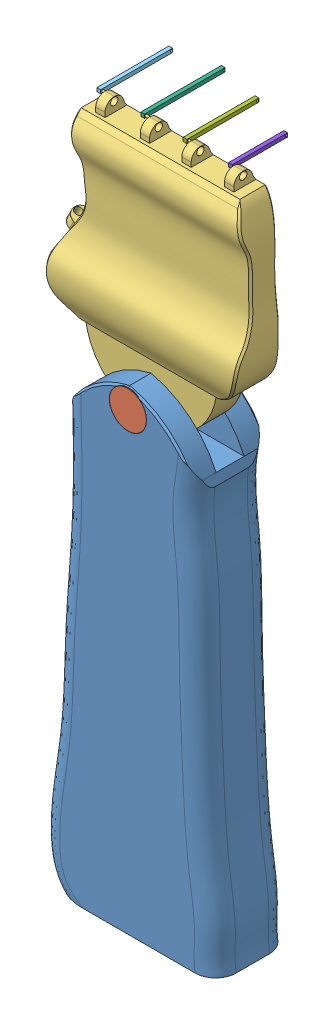
SolidWorks assembly Assem1, configuration Default. Lengths in mm.
Overall size (1345.11 2370.32 3373.58).
8 component instances, 8 part files, 14 mates.
Components (placement in the parent):
- arm2-1: arm2 [Default] at (-234.1441 930.3208 2564.8696) x (1 0 0) z (0 -1 0) size (1268.57 632.71 2564.87)
- armpin2-1: armpin2 [Default] at (-234.1441 1110.3208 2364.8696) size (200 200 400)
- palm2-1: palm2 [Default] at (-193.4419 1800.3208 2458.7662) x (1 0 0) z (0 -1 0) size (1069.09 253.19 1333.97)
- llink2palmThumb-1: llink2palmThumb [Default] at (-757.3795 1540.6952 2271.7924) x (0.892018 -0.452 0) z (0 0 1) size (20 20 462)
- link1palm-1: link1palm [Default] at (-638.703 2260.3208 2313.2524) x (0 1 0) z (0 0 1) size (20 20 387)
- llinkMiddle-1: llinkMiddle [Default] at (-406.703 2260.3208 2286.0724) x (0 1 0) z (0 0 1) size (20 20 434)
- llink2palmRing-1: llink2palmRing [Default] at (-175.0526 2260.3208 2313.2524) x (0 1 0) z (0 0 1) size (20 20 387)
- linklittle-1: linklittle [Default] at (64.9474 2260.3208 2353.4824) x (0 1 0) z (0 0 1) size (20 20 298)
Mates (geometry in assembly coordinates):
- Concentric1: concentric: cylinder of assembly; cylinder of assembly; cylinder of arm2-1 through (-234.1441 1110.3208 2364.8696) axis (0 0 1) radius 100; cylinder of armpin2-1 through (-234.1441 1110.3208 2764.8696) axis (0 0 -1) radius 100
- Coincident1: coincident: plane of assembly; plane of assembly; plane of arm2-1 through (-234.1441 930.3208 2764.8696) normal (0 0 1); plane of armpin2-1 through (-234.1441 1110.3208 2764.8696) normal (0 0 1)
- Concentric2: concentric: cylinder of assembly; cylinder of assembly; cylinder of armpin2-1 through (-234.1441 1110.3208 2764.8696) axis (0 0 -1) radius 100; cylinder of palm2-1 through (-234.1441 1110.3208 2450.7496) axis (0 0 1) radius 100
- Coincident2: coincident: plane of assembly; plane of assembly; plane of arm2-1 through (-584.1441 930.3208 2640.3696) normal (0 0 -1); plane of palm2-1 through (-584.1441 980.3208 2640.3696) normal (0 0 1)
- Concentric5: concentric: cylinder of assembly; cylinder of assembly; cylinder of palm2-1 through (-757.3795 1540.6952 2495.7524) axis (0.452 0.892018 0) radius 5.75; cylinder of llink2palmThumb-1 through (-757.3795 1540.6952 2495.7524) axis (0.452 0.892018 0) radius 5.75
- Concentric6: concentric: cylinder of assembly; cylinder of assembly; cylinder of palm2-1 through (-658.703 2260.3208 2495.7524) axis (1 0 0) radius 5.75; cylinder of link1palm-1 through (-638.703 2260.3208 2495.7524) axis (-1 0 0) radius 5.75
- Coincident5: coincident: plane of assembly; plane of assembly; plane of palm2-1 through (-658.703 2260.3208 2495.7524) normal (-1 0 0); plane of link1palm-1 through (-658.703 2260.3208 2313.2524) normal (-1 0 0)
- Coincident6: coincident: plane of assembly; plane of assembly; plane of palm2-1 through (-757.3795 1540.6952 2495.7524) normal (-0.452 -0.892018 0); plane of llink2palmThumb-1 through (-757.3795 1540.6952 2271.7924) normal (-0.452 -0.892018 0)
- Concentric7: concentric: cylinder of assembly; cylinder of assembly; cylinder of palm2-1 through (-426.703 2260.3208 2495.7524) axis (1 0 0) radius 5.75; cylinder of llinkMiddle-1 through (-406.703 2260.3208 2495.7524) axis (-1 0 0) radius 5.75
- Coincident7: coincident: plane of assembly; plane of assembly; plane of palm2-1 through (-426.703 2260.3208 2495.7524) normal (-1 0 0); plane of llinkMiddle-1 through (-426.703 2260.3208 2286.0724) normal (-1 0 0)
- Concentric8: concentric: cylinder of assembly; cylinder of assembly; cylinder of palm2-1 through (-195.0526 2260.3208 2495.7524) axis (1 0 0) radius 5.75; cylinder of llink2palmRing-1 through (-175.0526 2260.3208 2495.7524) axis (-1 0 0) radius 5.75
- Coincident8: coincident: plane of assembly; plane of assembly; plane of palm2-1 through (-195.0526 2260.3208 2495.7524) normal (-1 0 0); plane of llink2palmRing-1 through (-195.0526 2260.3208 2313.2524) normal (-1 0 0)
- Concentric9: concentric: cylinder of assembly; cylinder of assembly; cylinder of palm2-1 through (44.9474 2260.3208 2495.7524) axis (1 0 0) radius 5.75; cylinder of linklittle-1 through (64.9474 2260.3208 2495.7524) axis (-1 0 0) radius 5.75
- Coincident9: coincident: plane of assembly; plane of assembly; plane of palm2-1 through (44.9474 2260.3208 2495.7524) normal (-1 0 0); plane of linklittle-1 through (44.9474 2260.3208 2353.4824) normal (-1 0 0)
